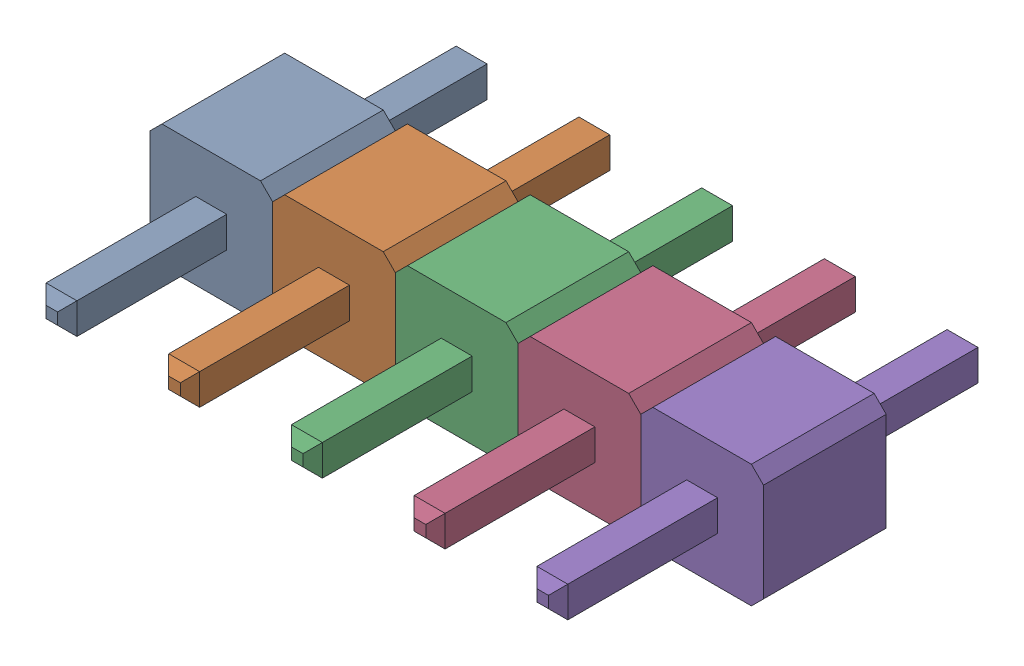
SolidWorks assembly PEC05SAAN, configuration Default. Lengths in mm.
Overall size (12.7 2.54 8.89).
5 component instances, 1 part files, 0 mates.
Components (placement in the parent):
- PEC05SAAN_1-1: PEC05SAAN_1 [Default] at origin size (2.54 2.54 8.89)
- PEC05SAAN_1-2: PEC05SAAN_1 [Default] at (2.54 0 0) size (2.54 2.54 8.89)
- PEC05SAAN_1-3: PEC05SAAN_1 [Default] at (5.08 0 0) size (2.54 2.54 8.89)
- PEC05SAAN_1-4: PEC05SAAN_1 [Default] at (7.62 0 0) size (2.54 2.54 8.89)
- PEC05SAAN_1-5: PEC05SAAN_1 [Default] at (10.16 0 0) size (2.54 2.54 8.89)
